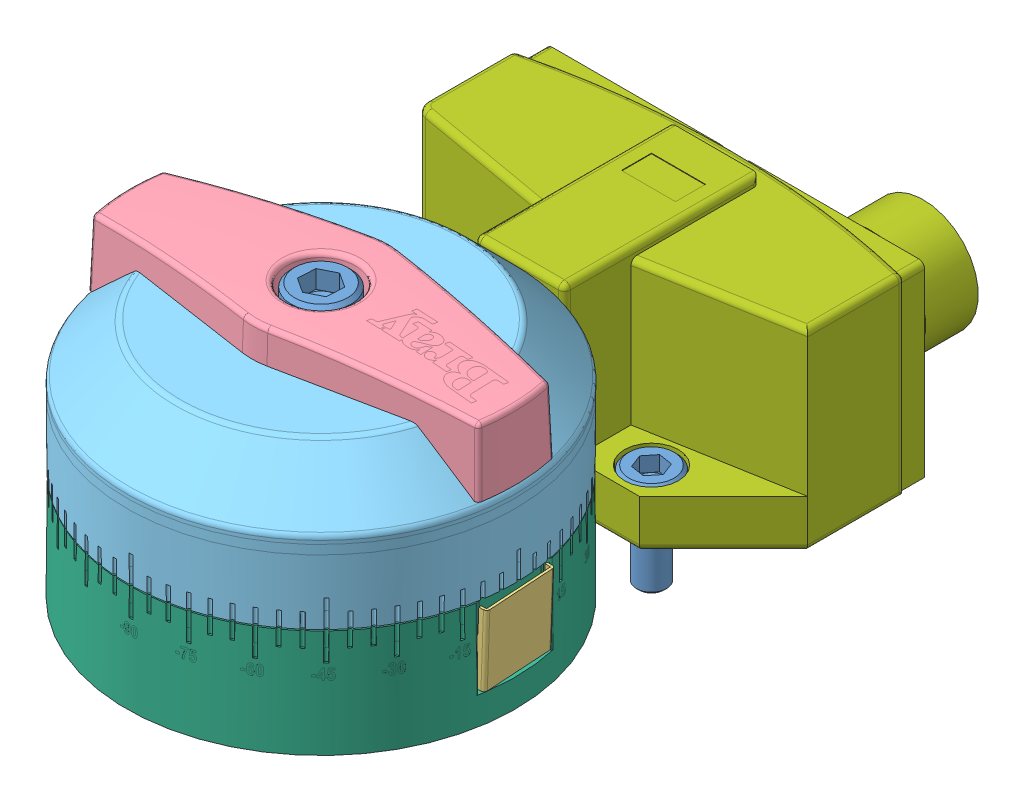
SolidWorks assembly Assem1, configuration Default. Lengths in mm.
Overall size (66.08 56.14 116.8).
10 component instances, 7 part files, 10 mates.
Components (placement in the parent):
- socket head cap screw_am-1: socket head cap screw_am [B18.3.1M - 5 x 0.8 x 12 Hex SHCS -- 12NHX] at (-17.2981 154.8404 -58.835) x (0 -1 0) z (-0.778168 0 0.628056) size (17 8.5 8.5)
- 54-048A-705P0-1: 54-048A-705P0 [Default] at (-2.2867 175.7964 -18.83) size (44.92 12.57 44.92)
- 54-000A-73500-1: 54-000A-73500 [Default] at (30.1626 159.4932 -19.487) x (-0.060648 0.001457 -0.998158) z (0.997549 -0.034869 -0.060662) size (12.19 11.94 6.35)
- 54-000A-92512-1: 54-000A-92512 [Default] at (-2.2867 182.3242 -18.83) x (-0.999645 0 0.026634) z (-0.026634 0 -0.999645) size (64.52 13.44 23.07)
- 54-000A-92511-1: 54-000A-92511 [Default] at (-2.2867 166.4492 -18.83) x (-0.999796 0 0.020182) z (-0.020182 0 -0.999796) size (64.76 21.97 66.01)
- 54-000A-92510-1: 54-000A-92510 [Default] at (-2.2867 148.3644 -18.83) x (-0.018943 0 -0.999821) z (0.999821 0 -0.018943) size (64.81 35.64 64.77)
- 54-000A-73500-2: 54-000A-73500 [Default] at (-2.8181 172.4182 -51.4869) x (-0.999979 0 0.00653) z (-0.00653 0 -0.999979) size (12.19 11.94 6.35)
- socket head cap screw_am-2: socket head cap screw_am [B18.3.1M - 6 x 1.0 x 30 Hex SHCS -- 30NHX] at (-2.2867 193.6582 -18.83) x (0 -1 0) z (-0.546944 0 0.837169) size (36 10 10)
- socket head cap screw_am-3: socket head cap screw_am [B18.3.1M - 5 x 0.8 x 12 Hex SHCS -- 12NHX] at (12.7247 154.8404 -58.835) x (0 -1 0) z (-0.778168 0 -0.628056) size (17 8.5 8.5)
- 54-0004-71104-1: 54-0004-71104 [Default] at (-2.2753 146.8404 -87.335) size (65 33.5 50.77)
Mates (geometry in assembly coordinates):
- Concentric1: concentric: cylinder of 54-000A-92512-1 through (-2.2867 182.3242 -18.83) axis (0 -1 0) radius 3.3; cylinder of 54-000A-92510-1 through (-2.2867 139.0306 -18.83) axis (0 1 0) radius 3.3
- Distance1: distance = 0.1778 mm: plane of 54-000A-92511-1 through (-2.0842 182.1464 -8.7991) normal (0 1 0); plane of 54-000A-92512-1 through (-2.0895 182.3242 -11.4286) normal (0 -1 0)
- Concentric2: concentric: cylinder of 54-000A-92512-1 through (-2.2867 182.3242 -18.83) axis (0 -1 0) radius 3.3; cylinder of 54-000A-92511-1 through (-2.2867 169.6376 -18.83) axis (0 1 0) radius 3.3
- Concentric3: concentric: cylinder of 54-000A-92512-1 through (-2.2867 182.3242 -18.83) axis (0 -1 0) radius 3.3; cylinder of socket head cap screw_am-2 through (-2.2867 225.4082 -18.83) axis (0 1 0) radius 3
- Parallel1: parallel: plane of 54-000A-73500-1 through (30.3241 153.519 -13.3983) normal (-0.034893 -0.999391 0.000661); plane of 54-000A-92510-1 through (28.137 153.0126 -19.4065) normal (0.034893 0.999391 -0.000661)
- Tangent1: tangent: face of 54-000A-92511-1; line of 54-000A-73500-2 through (3.2812 166.4492 -50.9933) axis (0 1 0)
- Coincident1: coincident: plane of 54-000A-92511-1 through (-2.0327 178.9714 -6.2469) normal (0 -1 0); plane of 54-000A-92510-1 through (-2.5297 178.9714 -31.6547) normal (0 1 0)
- Coincident2: coincident: circle of 54-000A-92512-1; plane of socket head cap screw_am-2 through (1.8991 187.6582 -16.0953) normal (0 -1 0)
- Coincident3: coincident: plane of 54-048A-705P0-1 through (-2.2867 175.7964 -18.83) normal (0 1 0); plane of 54-000A-92510-1 through (-2.6933 175.7964 -40.2892) normal (0 -1 0)
- Coincident4: coincident: plane of 54-000A-92511-1 through (-1.6867 166.4492 10.8913) normal (0 -1 0); plane of 54-000A-73500-2 through (3.2777 166.4492 -51.5267) normal (0 -1 0)
